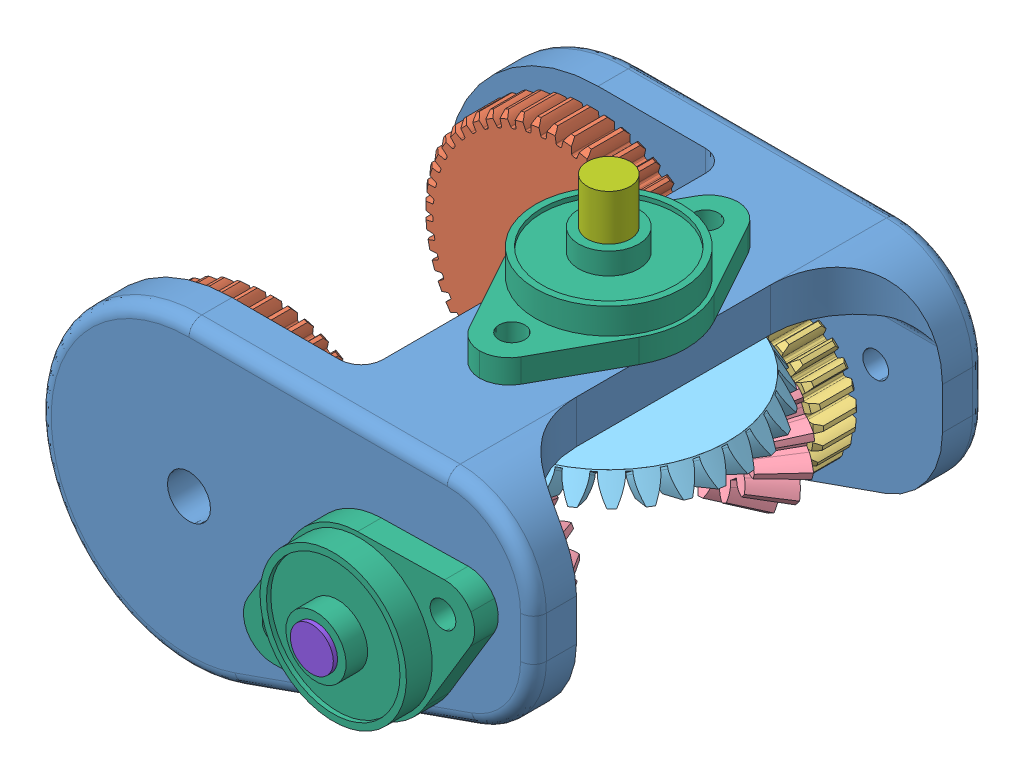
SolidWorks assembly ASSEMBLY Full Design 2nd Attempt - Holder Frame Design, configuration Default. Lengths in mm.
Overall size (131.96 113.3 137.94).
14 component instances, 8 part files, 37 mates.
Components (placement in the parent):
- Main Case-1: Main Case [Default] at (-4.7488 58.7631 49.9063) size (115 70 105)
- Secondary Big Spur Gear-1: Secondary Big Spur Gear [Default] at (-4.7488 58.7631 64.9063) x (-0.661995 -0.749508 0) z (0 0 1) size (62.4 62.32 10)
- Secondary Big Spur Gear-2: Secondary Big Spur Gear [Default] at (-4.7488 58.7631 139.9063) x (-0.978639 0.205585 0) z (0 0 1) size (62.4 62.32 10)
- Main Spur Gear - Copy-1: Main Spur Gear - Copy [Default] at (40.2512 58.7631 139.9063) x (0.91547 0.402387 0) z (0 0 1) size (32.38 32.33 10)
- Main Spur Gear - Copy-2: Main Spur Gear - Copy [Default] at (40.2512 58.7631 64.9063) x (-0.056478 -0.998404 0) z (0 0 1) size (32.38 32.33 10)
- Secondary Bevel Gear-1: Secondary Bevel Gear [Default] at (40.2512 58.7631 72.5284) x (0.056478 0.998404 0) z (0.998404 -0.056478 0) size (38.46 39.84 38.26)
- Secondary Bevel Gear-2: Secondary Bevel Gear [Default] at (40.2512 58.7631 132.2842) x (0.91547 0.402387 0) z (-0.402387 0.91547 0) size (38.46 39.84 38.26)
- Secondary Main Bevel Gear-1: Secondary Main Bevel Gear [Default] at (40.2512 76.0836 102.4063) x (-0.550514 0 0.834826) z (0.834826 0 0.550514) size (61.95 69.28 62)
- Main Slewing Bearing-1: Main Slewing Bearing [Default] at (40.2512 93.7631 102.4063) x (0 0 -1) z (1 0 0) size (60 15.5 36)
- Secondary Gear Shaft-1: Secondary Gear Shaft [Default] at (40.2512 119.8659 102.4063) x (0.550514 0 -0.834826) z (-0.834826 0 -0.550514) size (10 46 10)
- Secondary Gear Shaft Horizontal-1: Secondary Gear Shaft Horizontal [Default] at (40.2512 58.7631 171.3756) x (-0.91547 -0.402387 0) z (0.402387 -0.91547 0) size (10 46 10)
- Secondary Gear Shaft Horizontal-3: Secondary Gear Shaft Horizontal [Default] at (40.2512 58.7631 33.4369) x (-0.056478 -0.998404 0) z (-0.998404 0.056478 0) size (10 46 10)
- Main Slewing Bearing-2: Main Slewing Bearing [Default] at (40.2512 58.7631 49.9063) x (0.866025 0.5 0) z (-0.5 0.866025 0) size (60 15.5 36)
- Main Slewing Bearing-3: Main Slewing Bearing [Default] at (40.2512 58.7631 154.9063) x (0.866025 0.5 0) z (0.5 -0.866025 0) size (60 15.5 36)
Mates (geometry in assembly coordinates):
- Concentric1: concentric aligned: cylinder of Main Case-1 through (-4.7488 58.7631 144.9063) axis (0 0 1) radius 5; cylinder of Secondary Big Spur Gear-2 through (-4.7488 58.7631 134.9063) axis (0 0 1) radius 5
- Coincident1: coincident anti-aligned: plane of Main Case-1 through (-4.7488 58.7631 144.9063) normal (0 0 -1); plane of Secondary Big Spur Gear-2 through (-4.7488 58.7631 144.9063) normal (0 0 1)
- Concentric2: concentric anti-aligned: cylinder of Main Case-1 through (-4.7488 58.7631 59.9063) axis (0 0 -1) radius 5; cylinder of Secondary Big Spur Gear-1 through (-4.7488 58.7631 59.9063) axis (0 0 1) radius 5
- Coincident2: coincident anti-aligned: plane of Main Case-1 through (-4.7488 58.7631 59.9063) normal (0 0 1); plane of Secondary Big Spur Gear-1 through (-4.7488 58.7631 59.9063) normal (0 0 -1)
- Concentric3: concentric anti-aligned: cylinder of Main Case-1 through (40.2512 58.7631 59.9063) axis (0 0 -1) radius 5; cylinder of Main Spur Gear - Copy-2 through (40.2512 58.7631 59.9063) axis (0 0 1) radius 5
- Coincident3: coincident anti-aligned: plane of Main Case-1 through (-4.7488 58.7631 59.9063) normal (0 0 1); plane of Main Spur Gear - Copy-2 through (40.2512 58.7631 59.9063) normal (0 0 -1)
- GearMate1: gear = 60 : 30 mm: circle of Main Spur Gear - Copy-2; circle of Secondary Big Spur Gear-1
- Concentric5: concentric aligned: cylinder of Main Case-1 through (40.2512 58.7631 144.9063) axis (0 0 1) radius 5; cylinder of Main Spur Gear - Copy-1 through (40.2512 58.7631 134.9063) axis (0 0 1) radius 5
- Coincident4: coincident anti-aligned: plane of Main Case-1 through (-4.7488 58.7631 144.9063) normal (0 0 -1); plane of Main Spur Gear - Copy-1 through (40.2512 58.7631 144.9063) normal (0 0 1)
- GearMate2: gear = 60 : 30 mm: circle of Main Spur Gear - Copy-1; circle of Secondary Big Spur Gear-2
- Concentric7: concentric aligned: cylinder of Main Case-1 through (40.2512 58.7631 59.9063) axis (0 0 -1) radius 5; cylinder of Secondary Bevel Gear-1 through (40.2512 58.7631 81.9869) axis (0 0 -1) radius 5
- Coincident5: coincident aligned: plane of Main Spur Gear - Copy-2 through (47.353 60.3646 59.9063) normal (-0.998404 0.056478 0); plane of Secondary Bevel Gear-1 through (47.1271 56.371 81.9869) normal (-0.998404 0.056478 0)
- Concentric8: concentric aligned: cylinder of Main Spur Gear - Copy-1 through (40.2512 58.7631 134.9063) axis (0 0 1) radius 5; cylinder of Secondary Bevel Gear-2 through (40.2512 58.7631 122.8257) axis (0 0 1) radius 5
- Coincident6: coincident aligned: plane of Main Spur Gear - Copy-1 through (35.6036 64.3666 134.9063) normal (0.402387 -0.91547 0); plane of Secondary Bevel Gear-2 through (35.6036 64.3666 122.8257) normal (0.402387 -0.91547 0)
- Concentric9: concentric aligned: cylinder of Main Case-1 through (40.2512 23.7631 102.4063) axis (0 1 0) radius 5; cylinder of Secondary Main Bevel Gear-1 through (40.2512 69.8591 102.4063) axis (0 1 0) radius 5
- Coincident7: coincident: point of Secondary Bevel Gear-1; point of Secondary Main Bevel Gear-1
- Coincident8: coincident: line of Secondary Bevel Gear-2 through (40.2512 58.7631 102.4063) axis (-0.457735 -0.201194 0.866025)
- GearMate3: gear = 34.5 : 60 mm: circle of Secondary Main Bevel Gear-1; circle of Secondary Bevel Gear-1
- GearMate4: gear = 60 : 34.5 mm: circle of Secondary Bevel Gear-2; circle of Secondary Main Bevel Gear-1
- Concentric11: concentric aligned: cylinder of Main Case-1 through (40.2512 23.7631 102.4063) axis (0 1 0) radius 5; cylinder of Main Slewing Bearing-1 through (40.2512 93.7631 102.4063) axis (0 1 0) radius 5
- Concentric12: concentric anti-aligned: cylinder of Main Case-1 through (40.2512 93.7631 79.9063) axis (0 1 0) radius 3; cylinder of Main Slewing Bearing-1 through (40.2512 99.2631 79.9063) axis (0 -1 0) radius 3
- Coincident9: coincident anti-aligned: plane of Main Case-1 through (-4.7488 93.7631 59.9063) normal (0 1 0); plane of Main Slewing Bearing-1 through (40.2512 93.7631 102.4063) normal (0 -1 0)
- Concentric13: concentric aligned: cylinder of Main Slewing Bearing-1 through (40.2512 93.7631 102.4063) axis (0 1 0) radius 5; cylinder of Secondary Gear Shaft-1 through (40.2512 73.8659 102.4063) axis (0 1 0) radius 5
- Coincident10: coincident aligned: plane of Secondary Main Bevel Gear-1 through (51.1253 73.8659 85.9163) normal (0 -1 0); plane of Secondary Gear Shaft-1 through (40.2512 73.8659 102.4063) normal (0 -1 0)
- Coincident11: coincident aligned: plane of Secondary Main Bevel Gear-1 through (45.1779 69.8591 103.2594) normal (-0.550514 0 0.834826); plane of Secondary Gear Shaft-1 through (43.8567 83.8659 102.3882) normal (-0.550514 0 0.834826)
- Concentric14: concentric aligned: cylinder of Secondary Bevel Gear-1 through (40.2512 58.7631 81.9869) axis (0 0 -1) radius 5; cylinder of Secondary Gear Shaft Horizontal-3 through (40.2512 58.7631 79.4369) axis (0 0 -1) radius 5
- Coincident12: coincident aligned: plane of Secondary Bevel Gear-1 through (39.7282 49.5177 79.4369) normal (0 0 1); plane of Secondary Gear Shaft Horizontal-3 through (40.2512 58.7631 79.4369) normal (0 0 1)
- Coincident15: coincident aligned: plane of Secondary Bevel Gear-1 through (44.7135 56.5075 81.9869) normal (0.056478 0.998404 0); plane of Secondary Gear Shaft Horizontal-3 through (43.1335 56.5969 69.4369) normal (0.056478 0.998404 0)
- Concentric15: concentric aligned: cylinder of Secondary Bevel Gear-2 through (40.2512 58.7631 122.8257) axis (0 0 1) radius 5; cylinder of Secondary Gear Shaft Horizontal-1 through (40.2512 58.7631 125.3756) axis (0 0 1) radius 5
- Coincident16: coincident aligned: plane of Secondary Bevel Gear-2 through (31.7738 55.0369 125.3756) normal (0 0 -1); plane of Secondary Gear Shaft Horizontal-1 through (40.2512 58.7631 125.3756) normal (0 0 -1)
- Coincident17: coincident aligned: plane of Secondary Bevel Gear-2 through (36.5763 62.1536 122.8257) normal (0.91547 0.402387 0); plane of Secondary Gear Shaft Horizontal-1 through (37.2131 60.7048 135.3756) normal (0.91547 0.402387 0)
- Concentric16: concentric aligned: cylinder of Secondary Gear Shaft Horizontal-3 through (40.2512 58.7631 79.4369) axis (0 0 -1) radius 5; cylinder of Main Slewing Bearing-2 through (40.2512 58.7631 49.9063) axis (0 0 -1) radius 5
- Coincident18: coincident anti-aligned: plane of Main Case-1 through (-4.7488 58.7631 49.9063) normal (0 0 -1); plane of Main Slewing Bearing-2 through (40.2512 58.7631 49.9063) normal (0 0 1)
- Concentric17: concentric anti-aligned: cylinder of Main Case-1 through (59.7368 70.0131 154.9063) axis (0 0 -1) radius 3; cylinder of Main Slewing Bearing-2 through (59.7368 70.0131 44.4063) axis (0 0 1) radius 3
- Concentric18: concentric aligned: cylinder of Secondary Gear Shaft Horizontal-1 through (40.2512 58.7631 125.3756) axis (0 0 1) radius 5; cylinder of Main Slewing Bearing-3 through (40.2512 58.7631 215.9412) axis (0 0 1) radius 5
- Concentric19: concentric aligned: cylinder of Main Case-1 through (59.7368 70.0131 154.9063) axis (0 0 -1) radius 3; cylinder of Main Slewing Bearing-3 through (59.7368 70.0131 221.4412) axis (0 0 -1) radius 3
- Coincident19: coincident anti-aligned: plane of Main Case-1 through (-4.7488 58.7631 154.9063) normal (0 0 1); plane of Main Slewing Bearing-3 through (40.2512 58.7631 154.9063) normal (0 0 -1)
